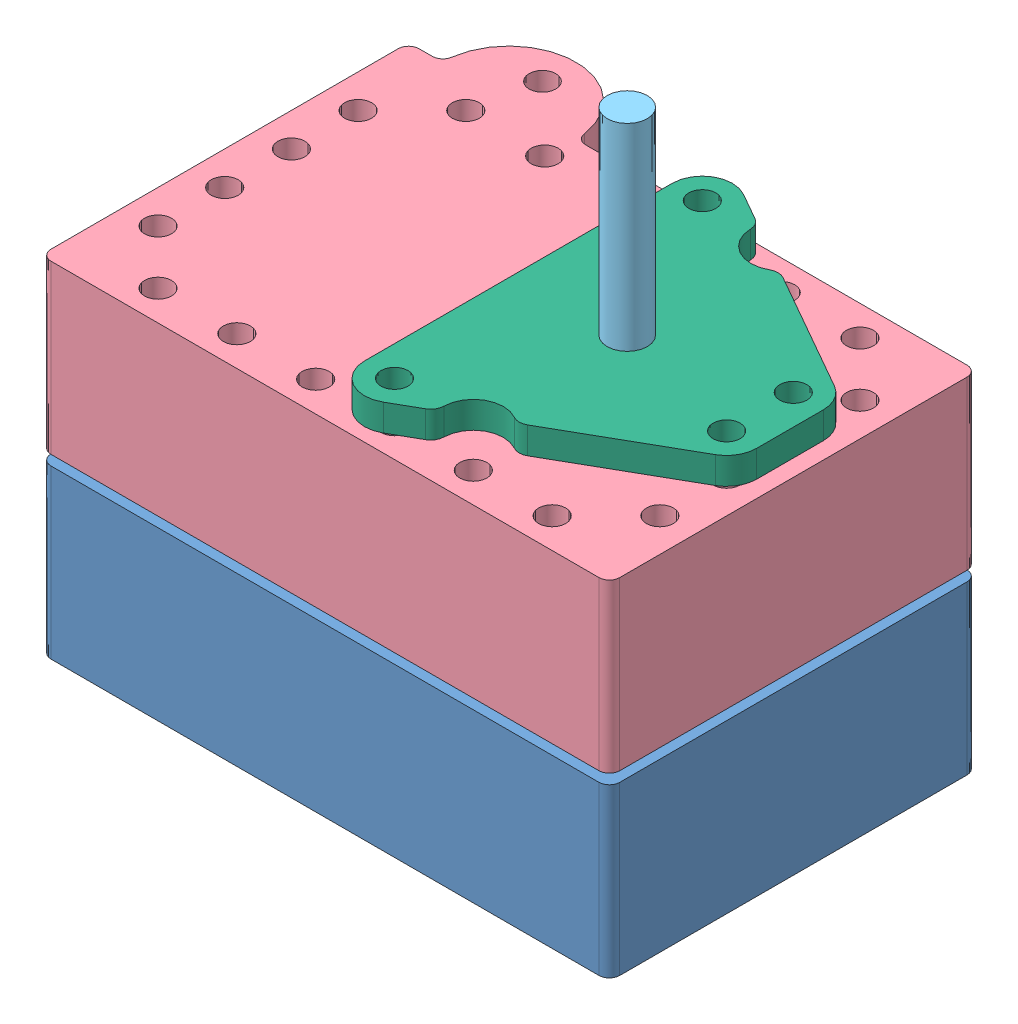
SolidWorks assembly MCHCKcase_pub, configuration Default. Lengths in mm.
Overall size (85 87 65).
8 component instances, 8 part files, 15 mates.
Components (placement in the parent):
- MCHCKcasebottom_pub-1: MCHCKcasebottom_pub [Default] at (-121.7366 -16.1075 71.7629) size (85 25 55)
- mchck-1: mchck [Default] at (-102.8803 -1.6075 53.9025) size (47.2 8 18.9)
- coincell-1: coincell [Default] at (-88.5227 6.3925 44.4022) x (0 0 -1) z (1 0 0) size (23 7 27)
- MCHCKcasetop_pub-1: MCHCKcasetop_pub [Default] at (-36.7366 35.3925 71.7629) x (-1 0 0) z (0 0 1) size (85 25 65)
- temperatureSensor-1: temperatureSensor [Default] at (-61.5666 20.8925 44.2629) size (6 50 6)
- mchcksensorholder_pub-2: mchcksensorholder_pub [Default] at (-37.2366 41.3925 44.2629) x (-1 0 0) z (0 0 1) size (40.61 5 55)
- MCHCKsensorgasket_pub-1: MCHCKsensorgasket_pub [Default] at (-61.5666 35.3925 44.2629) size (13 2 13)
- MCHCKcasegasket_pub-1: MCHCKcasegasket_pub [Default] at (-112.7366 8.6425 63.2629) size (66.8 2 37.8)
Mates (geometry in assembly coordinates):
- Coincident1: coincident anti-aligned: plane of MCHCKcasebottom_pub-1 through (-121.7366 -1.6075 71.7629) normal (0 1 0); plane of mchck-1 through (-102.8803 -1.6075 53.9025) normal (0 -1 0)
- Coincident3: coincident anti-aligned: plane of mchck-1 through (-102.8803 6.3925 53.9025) normal (0 1 0); plane of coincell-1 through (-88.5227 6.3925 44.4022) normal (0 -1 0)
- Coincident7: coincident aligned: plane of MCHCKcasebottom_pub-1 through (-121.7366 8.8925 71.7629) normal (0 0 1); plane of MCHCKcasetop_pub-1 through (-36.7366 10.3925 71.7629) normal (0 0 1)
- Coincident8: coincident aligned: plane of MCHCKcasebottom_pub-1 through (-36.7366 8.8925 71.7629) normal (1 0 0); plane of MCHCKcasetop_pub-1 through (-36.7366 10.3925 71.7629) normal (1 0 0)
- Coincident9: coincident anti-aligned: circle of MCHCKcasetop_pub-1; circle of temperatureSensor-1
- Parallel1: parallel aligned: plane of MCHCKcasetop_pub-1 through (-36.7366 10.3925 71.7629) normal (1 0 0); plane of mchcksensorholder_pub-2 through (-37.2366 37.3925 49.2479) normal (1 0 0)
- Concentric2: concentric anti-aligned: cylinder of temperatureSensor-1 through (-61.5666 70.8925 44.2629) axis (0 -1 0) radius 3; cylinder of mchcksensorholder_pub-2 through (-61.5666 37.3925 44.2629) axis (0 1 0) radius 3
- Coincident10: coincident anti-aligned: plane of MCHCKcasebottom_pub-1 through (-121.7366 8.6425 71.7629) normal (0 1 0); plane of MCHCKcasegasket_pub-1 through (-112.7366 8.6425 63.2629) normal (0 -1 0)
- Coincident11: coincident anti-aligned: plane of MCHCKcasebottom_pub-1 through (-121.7366 8.6425 71.7629) normal (0 1 0); plane of MCHCKcasegasket_pub-1 through (-112.7366 8.6425 63.2629) normal (0 -1 0)
- Coincident12: coincident: line of MCHCKcasebottom_pub-1 through (-111.1866 8.8925 63.2629) axis (1 0 0); plane of MCHCKcasegasket_pub-1 through (-112.7366 10.6425 63.2629) normal (0 0 1)
- Coincident16: coincident: line of MCHCKcasebottom_pub-1 through (-112.7366 8.8925 26.8129) axis (0 0 1); plane of MCHCKcasegasket_pub-1 through (-112.7366 10.6425 63.2629) normal (-1 0 0)
- Coincident17: coincident anti-aligned: plane of MCHCKcasetop_pub-1 through (-36.7366 10.6425 71.7629) normal (0 -1 0); plane of MCHCKcasegasket_pub-1 through (-112.7366 10.6425 63.2629) normal (0 1 0)
- Coincident19: coincident anti-aligned: plane of mchcksensorholder_pub-2 through (-41.7366 37.3925 49.2479) normal (0 -1 0); plane of MCHCKsensorgasket_pub-1 through (-14.4261 37.3925 33.1742) normal (0 1 0)
- Coincident21: coincident anti-aligned: plane of MCHCKcasetop_pub-1 through (-106.7366 35.3925 16.7629) normal (0 1 0); plane of MCHCKsensorgasket_pub-1 through (-61.5666 35.3925 44.2629) normal (0 -1 0)
- Concentric3: concentric aligned: cylinder of temperatureSensor-1 through (-61.5666 70.8925 44.2629) axis (0 -1 0) radius 3; cylinder of MCHCKsensorgasket_pub-1 through (-61.5666 37.3925 44.2629) axis (0 -1 0) radius 3
